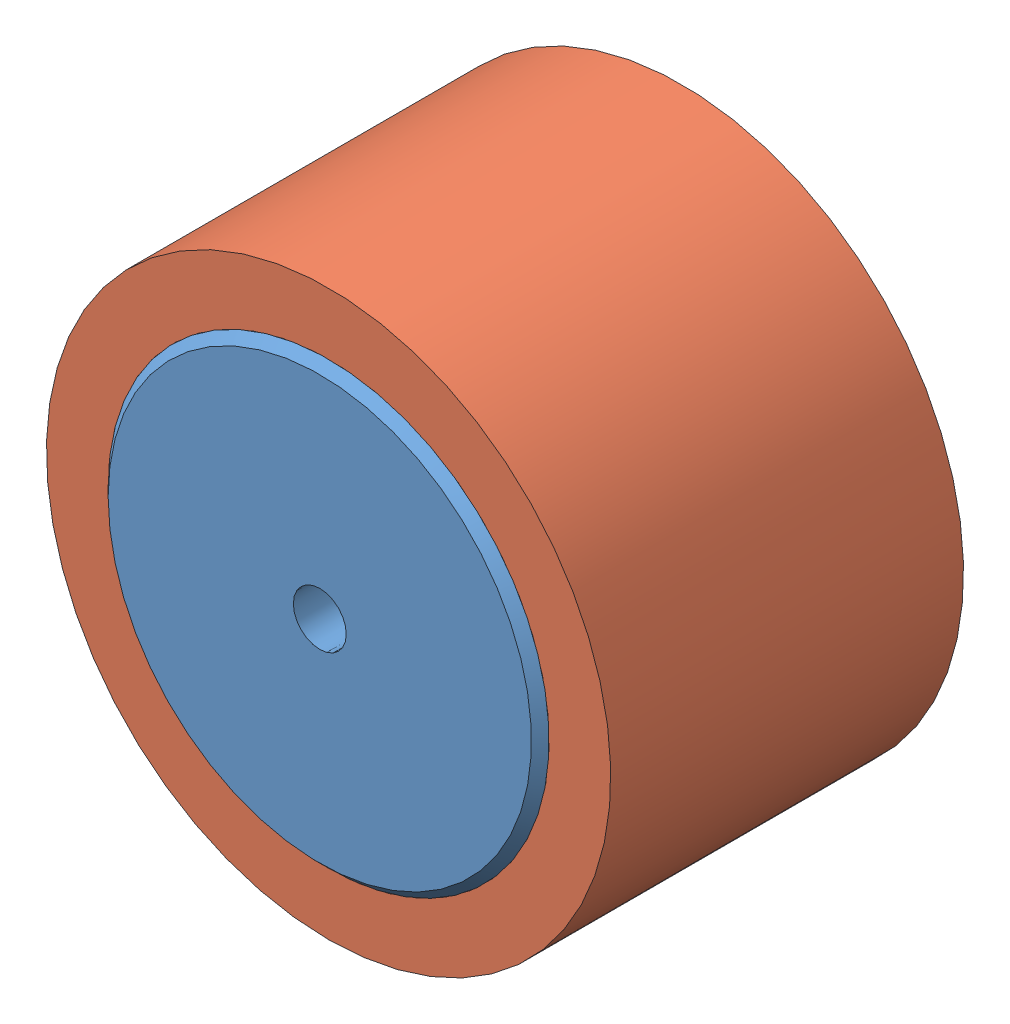
SolidWorks assembly Roda_StickyMAX-S15-32mm, configuration Valor predeterminado. Lengths in mm.
Overall size (32 32 21).
3 component instances, 3 part files, 0 mates.
Components (placement in the parent):
- Roda_sumo500-1: Roda_sumo500 [Valor predeterminado] x (0 0 -1) z (1 0 0) size (21 25 25)
- Roda_sumo500-pneu-1: Roda_sumo500-pneu [Valor predeterminado] x (0 0 1) z (-1 0 0) size (20.05 32 32)
- socket set screw flat point_am(B18.3.6M - M4 x 0.7 x 5 Hex Socket Flat Pt. SS --S)-1: socket set screw flat point_am(B18.3.6M - M4 x 0.7 x 5 Hex Socket Flat Pt. SS --S) [Valor predeterminado] at (0 6.5 6.5) x (0 -1 0) z (0 0 1) size (5 4 4)
